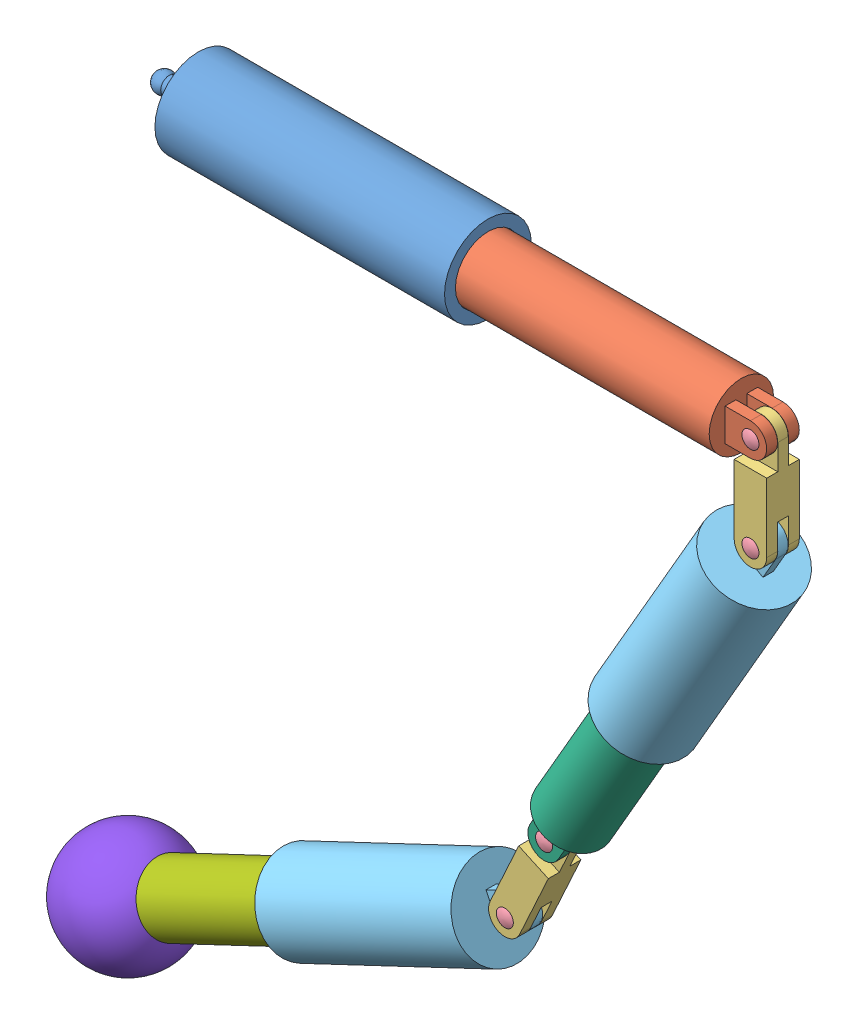
SolidWorks assembly Spider Chair Leg, configuration Default. Lengths in mm.
Overall size (1051.36 1165.11 159).
13 component instances, 8 part files, 41 mates.
Components (placement in the parent):
- Leg Segment 1 - Top-1: Leg Segment 1 - Top [Default] at origin size (460.49 120 120)
- Leg Segment 1 - Bottom-2: Leg Segment 1 - Bottom [Default] at (375 0 0) size (447.5 109 109)
- Knee-2: Knee [Default] at (605 -35 0) x (0 -1 0) z (0 0 1) size (175 45 45)
- Leg Bolt-1: Leg Bolt [Default] at (605 0 0) x (0 -1 0) z (1 0 0) size (23.5 51 23.5)
- Leg Segment 2 and 3 - Top-1: Leg Segment 2 and 3 - Top [Default] at (512.5 -290.2147 0) x (-0.5 -0.866025 0) z (0 0 1) size (357.5 120 120)
- Leg Bolt-2: Leg Bolt [Default] at (605 -130 0) x (0 -1 0) z (1 0 0) size (23.5 51 23.5)
- Leg Segment 2- Bottom-2: Leg Segment 2- Bottom [Default] at (397.5 -489.4005 0) x (-0.5 -0.866025 0) z (0 0 1) size (297.5 109 109)
- Knee-4: Knee [Default] at (305.4089 -655.448 0) x (-0.416889 -0.908957 0) z (0 0 1) size (175 45 45)
- Leg Bolt-4: Leg Bolt [Default] at (320 -623.6345 0) x (-0.5 -0.866025 0) z (0.866025 -0.5 0) size (23.5 51 23.5)
- Leg Segment 2 and 3 - Top-2: Leg Segment 2 and 3 - Top [Default] at (98.6343 -821.0401 0) x (-0.903622 -0.42833 0) z (0 0 1) size (357.5 120 120)
- Leg Segment 3- Bottom-1: Leg Segment 3- Bottom [Default] at (-109.1988 -919.5561 0) x (-0.903622 -0.42833 0) z (0 0 1) size (240 109 109)
- Leg Bolt-5: Leg Bolt [Default] at (265.8044 -741.7989 0) x (-0.416889 -0.908957 0) z (0.908957 -0.416889 0) size (23.5 51 23.5)
- Foot-1: Foot [Default] at (-277.2555 -999.2175 0) x (0 0 -1) z (-0.42833 0.903622 0) size (159 199 159)
Mates (geometry in assembly coordinates):
- Coincident1: coordinate: point of Leg Segment 1 - Top-1
- Concentric1: concentric aligned: cylinder of Leg Segment 1 - Top-1 through (-220 0 0) axis (-1 0 0) radius 55; cylinder of Leg Segment 1 - Bottom-2 through (180 0 0) axis (-1 0 0) radius 54.5
- Coincident2: coincident aligned: plane of Leg Segment 1 - Top-1 through (0 0 0) normal (0 0 1)
- Coincident3: coincident aligned: plane of Leg Segment 1 - Bottom-2 through (375 0 0) normal (0 0 1)
- LimitDistance1: limit distance = 0 mm anti-aligned: plane of Leg Segment 1 - Bottom-2 through (200 44.5 0) normal (1 0 0); plane of Leg Segment 1 - Top-1 through (200 55 0) normal (-1 0 0)
- Coincident5: coincident aligned: plane of Knee-2 through (605 -35 0) normal (0 0 1)
- Concentric3: concentric anti-aligned: cylinder of Leg Segment 1 - Bottom-2 through (605 0 22.5) axis (0 0 -1) radius 10; cylinder of Knee-2 through (605 0 -7.25) axis (0 0 1) radius 10
- LimitAngle3: limit planar angle = 1.570796 rad anti-aligned: plane of Knee-2 through (582.5 -35 -7.25) normal (-1 0 0); plane of Leg Segment 1 - Bottom-2 through (570 -22.5 22.5) normal (0 -1 0)
- Concentric4: concentric aligned: cylinder of Knee-2 through (605 0 -7.25) axis (0 0 1) radius 10; cylinder of Leg Bolt-1 through (605 0 -22.5) axis (0 0 1) radius 9.75
- Coincident7: coincident anti-aligned: plane of Leg Segment 1 - Bottom-2 through (605 0 22.5) normal (0 0 1); plane of Leg Bolt-1 through (605 0 22.5) normal (0 0 -1)
- Concentric5: concentric anti-aligned: cylinder of Knee-2 through (605 -130 22.5) axis (0 0 -1) radius 10; cylinder of Leg Segment 2 and 3 - Top-1 through (605 -130 -7.25) axis (0 0 1) radius 10
- Concentric7: concentric aligned: cylinder of Leg Segment 2 and 3 - Top-1 through (605 -130 -7.25) axis (0 0 1) radius 10; cylinder of Leg Bolt-2 through (605 -130 -22.5) axis (0 0 1) radius 9.75
- Coincident10: coincident anti-aligned: plane of Knee-2 through (582.5 -95 22.5) normal (0 0 1); plane of Leg Bolt-2 through (605 -130 22.5) normal (0 0 -1)
- Coincident12: coincident aligned: plane of Leg Bolt-2 through (605 -130 0) normal (1 0 0); plane of Knee-2 through (605 -35 0) normal (1 0 0)
- Coincident14: coincident aligned: plane of Knee-2 through (605 -35 0) normal (1 0 0); plane of Leg Bolt-1 through (605 0 0) normal (1 0 0)
- LimitAngle4: limit planar angle = 2.617994 rad anti-aligned: plane of Leg Segment 2 and 3 - Top-1 through (568.0144 -149.0609 -7.25) normal (-0.866025 0.5 0); plane of Knee-2 through (582.5 -35 -7.25) normal (-1 0 0)
- Concentric8: concentric anti-aligned: cylinder of Knee-2 through (605 -130 22.5) axis (0 0 -1) radius 10; cylinder of Leg Bolt-2 through (605 -130 -22.5) axis (0 0 1) radius 9.75
- Width3: width aligned: plane of Knee-2 through (605 -130 -7.5) normal (0 0 1); plane of Leg Segment 2 and 3 - Top-1 through (605 -130 7.5) normal (0 0 -1); plane of Knee-2 through (605 -130 7.25) normal (0 0 1); plane of Leg Segment 2 and 3 - Top-1 through (605 -130 -7.25) normal (0 0 -1)
- Coincident18: coincident aligned: plane of Leg Segment 2 and 3 - Top-1 through (512.5 -290.2147 0) normal (0.866025 -0.5 0); plane of Leg Segment 2- Bottom-2 through (397.5 -489.4005 0) normal (0.866025 -0.5 0)
- Concentric15: concentric aligned: cylinder of Leg Segment 2 and 3 - Top-1 through (587.5 -160.3109 0) axis (0.5 0.866025 0) radius 55; cylinder of Leg Segment 2- Bottom-2 through (457.5 -385.4775 0) axis (0.5 0.866025 0) radius 54.5
- Concentric16: concentric aligned: cylinder of Leg Segment 2 and 3 - Top-1 through (587.5 -160.3109 0) axis (0.5 0.866025 0) radius 45; cylinder of Leg Segment 2- Bottom-2 through (457.5 -385.4775 0) axis (0.5 0.866025 0) radius 44.5
- LimitDistance3: limit distance = 0 mm anti-aligned: plane of Leg Segment 2- Bottom-2 through (486.0381 -425.048 0) normal (-0.5 -0.866025 0); plane of Leg Segment 2 and 3 - Top-1 through (495.1314 -430.298 0) normal (0.5 0.866025 0)
- Concentric17: concentric anti-aligned: cylinder of Leg Segment 2- Bottom-2 through (320 -623.6345 22.5) axis (0 0 -1) radius 10; cylinder of Knee-4 through (320 -623.6345 -7.25) axis (0 0 1) radius 10
- Width4: width anti-aligned: plane of Leg Segment 2- Bottom-2 through (320 -623.6345 -7.5) normal (0 0 1); plane of Knee-4 through (320 -623.6345 7.5) normal (0 0 -1); plane of Leg Segment 2- Bottom-2 through (320 -623.6345 -7.25) normal (0 0 -1); plane of Knee-4 through (320 -623.6345 7.25) normal (0 0 1)
- Concentric18: concentric aligned: cylinder of Knee-4 through (320 -623.6345 -7.25) axis (0 0 1) radius 10; cylinder of Leg Bolt-4 through (320 -623.6345 -22.5) axis (0 0 1) radius 9.75
- Coincident20: coincident anti-aligned: plane of Leg Segment 2- Bottom-2 through (320 -623.6345 22.5) normal (0 0 1); plane of Leg Bolt-4 through (320 -623.6345 22.5) normal (0 0 -1)
- LimitAngle5: limit planar angle = 0.093579 rad aligned: plane of Knee-4 through (325.8604 -664.828 -7.25) normal (0.908957 -0.416889 0); plane of Leg Segment 2- Bottom-2 through (356.9856 -604.5736 -22.5) normal (0.866025 -0.5 0)
- Coincident21: coincident aligned: plane of Leg Segment 2- Bottom-2 through (397.5 -489.4005 0) normal (0.866025 -0.5 0); plane of Leg Bolt-4 through (320 -623.6345 0) normal (0.866025 -0.5 0)
- Width5: width anti-aligned: plane of Knee-4 through (255 -736.2178 -7.5) normal (0 0 1); plane of Leg Segment 2 and 3 - Top-2 through (255 -736.2178 7.5) normal (0 0 -1); plane of Knee-4 through (255 -736.2178 -7.25) normal (0 0 -1); plane of Leg Segment 2 and 3 - Top-2 through (255 -736.2178 7.25) normal (0 0 1)
- Concentric19: concentric anti-aligned: cylinder of Knee-4 through (255 -736.2178 22.5) axis (0 0 -1) radius 10; cylinder of Leg Segment 2 and 3 - Top-2 through (255 -736.2178 -7.25) axis (0 0 1) radius 10
- Concentric20: concentric: cylinder of Leg Segment 2 and 3 - Top-2 through (265.8044 -741.7989 -7.25) axis (0 0 1) radius 10; cylinder of Leg Bolt-5 through (265.8044 -741.7989 -22.5) axis (0 0 1) radius 9.75
- Coincident22: coincident: plane of Knee-4 through (259.944 -700.6054 22.5) normal (0 0 1); plane of Leg Bolt-5 through (265.8044 -741.7989 22.5) normal (0 0 -1)
- Concentric21: concentric aligned: cylinder of Leg Segment 2 and 3 - Top-2 through (222.1108 -748.1885 0) axis (0.939693 0.34202 0) radius 55; cylinder of Leg Segment 3- Bottom-1 through (-22.2093 -837.1137 0) axis (0.939693 0.34202 0) radius 54.5
- Concentric22: concentric aligned: cylinder of Leg Segment 2 and 3 - Top-2 through (222.1108 -748.1885 0) axis (0.939693 0.34202 0) radius 45; cylinder of Leg Segment 3- Bottom-1 through (-22.2093 -837.1137 0) axis (0.939693 0.34202 0) radius 44.5
- LimitDistance4: limit distance = 0 mm anti-aligned: plane of Leg Segment 3- Bottom-1 through (0.2241 -916.9342 0) normal (-0.903622 -0.42833 0); plane of Leg Segment 2 and 3 - Top-2 through (4.7216 -926.4222 0) normal (0.903622 0.42833 0)
- Coincident24: coincident aligned: plane of Leg Segment 2 and 3 - Top-2 through (81.1569 -799.4915 0) normal (0.34202 -0.939693 0); plane of Leg Segment 3- Bottom-1 through (-134.9724 -878.1561 0) normal (0.34202 -0.939693 0)
- LimitAngle7: limit planar angle = 2.443461 rad anti-aligned: plane of Leg Segment 2 and 3 - Top-2 through (224.5402 -736.459 -7.25) normal (-0.42833 0.903622 0); plane of Knee-4 through (284.9573 -646.068 -7.25) normal (-0.908957 0.416889 0)
- Concentric23: concentric anti-aligned: cylinder of Leg Segment 3- Bottom-1 through (-197.4443 -900.8941 0) axis (0.939693 0.34202 0) radius 22.5; cylinder of Foot-1 through (-384.4432 -968.9561 0) axis (-0.939693 -0.34202 0) radius 22
- Coincident26: coincident anti-aligned: plane of Leg Segment 3- Bottom-1 through (-197.4443 -900.8941 0) normal (-0.939693 -0.34202 0); plane of Foot-1 through (-197.4443 -900.8941 0) normal (0.939693 0.34202 0)
- Coincident27: coincident anti-aligned: plane of Leg Segment 3- Bottom-1 through (-134.9724 -878.1561 0) normal (0.34202 -0.939693 0); plane of Foot-1 through (-309.7376 -941.7655 0) normal (-0.34202 0.939693 0)
- Coincident28: coincident aligned: plane of Knee-4 through (305.4089 -655.448 0) normal (0.908957 -0.416889 0); plane of Leg Bolt-5 through (265.8044 -741.7989 0) normal (0.908957 -0.416889 0)
